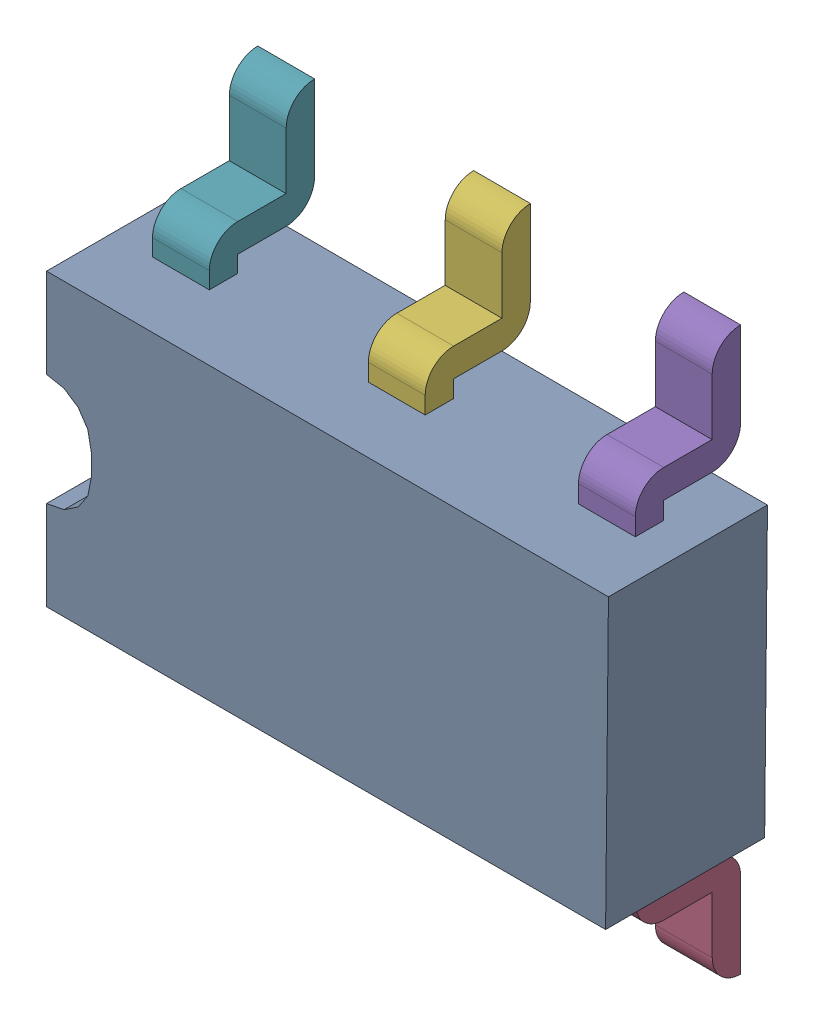
SolidWorks assembly Open CASCADE STEP translator 6.8 1.31.1, configuration Défaut. Lengths in mm.
Overall size (2.51 2.51 0.76).
7 component instances, 7 part files, 0 mates.
Components (placement in the parent):
- Body_1_15-1: Body_1_15 [Défaut] at origin size (2.51 1.3 0.71)
- Pin_1_11-1: Pin_1_11 [Défaut] at (-2.1844 -0.254 0) x (0 1 0) z (0 0 1) size (0.63 0.25 0.47)
- Pin_2_11-1: Pin_2_11 [Défaut] at (-1.2446 -1.1938 0) x (0 1 0) z (0 0 1) size (0.63 0.25 0.47)
- Pin_3_7-1: Pin_3_7 [Défaut] at (-0.2794 -2.159 0) x (0 1 0) z (0 0 1) size (0.63 0.25 0.47)
- Pin_4_5-1: Pin_4_5 [Défaut] at (-0.2267 2.1106 0) x (-0.002065 -0.999998 0) z (0 0 1) size (0.59 0.25 0.47)
- Pin_5_4-1: Pin_5_4 [Défaut] at (-1.1684 1.1708 0) x (-0.002073 -0.999998 0) z (0 0 1) size (0.58 0.25 0.47)
- Pin_6_4-1: Pin_6_4 [Défaut] at (-2.1356 0.2056 0) x (-0.002061 -0.999998 0) z (0 0 1) size (0.58 0.25 0.47)
